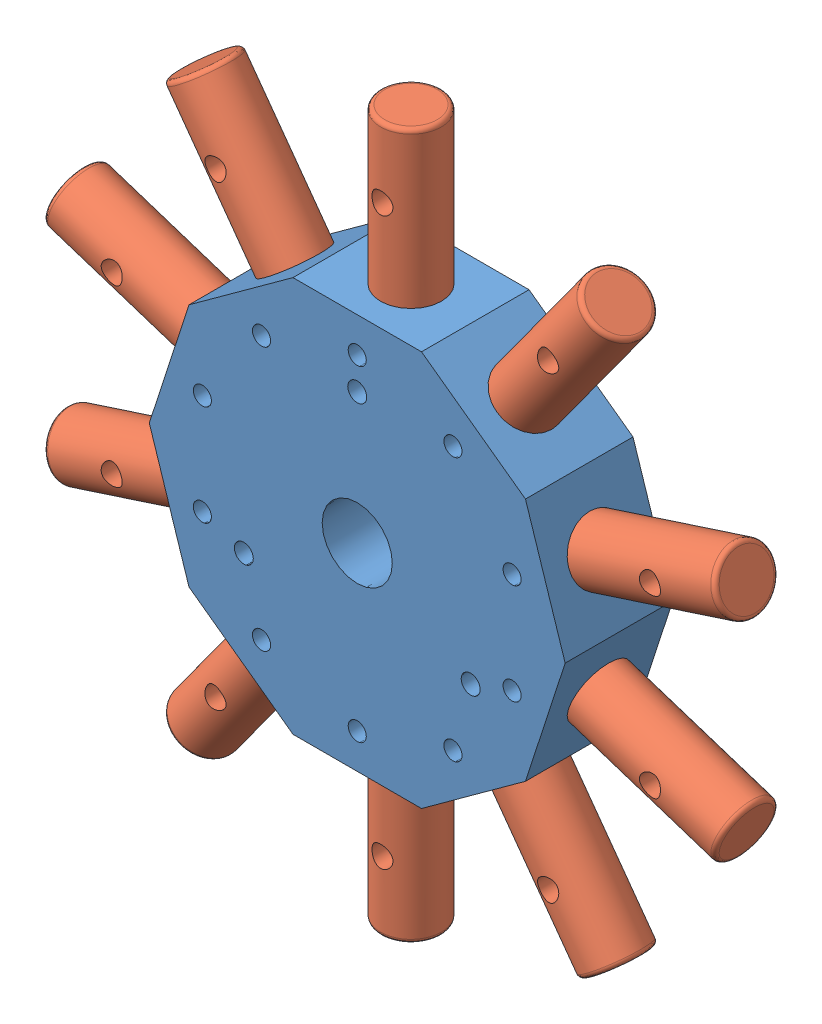
SolidWorks assembly RR2 Hub Subassembly, configuration Default. Lengths in mm.
Overall size (125.44 128.31 19.56).
11 component instances, 2 part files, 21 mates.
Components (placement in the parent):
- RR2 Hub Rev B-1: RR2 Hub Rev B [Default] at (9.4688 34.1785 19.558) size (75.62 71.92 19.56)
- RR2 Peg-1: RR2 Peg [Default] at (23.1405 52.9959 9.779) x (0.809017 -0.587785 0) z (0 0 1) size (11.05 40.89 11.05)
- RR2 Peg-2: RR2 Peg [Default] at (9.4688 57.4381 9.779) x (-1 0 0) z (0 0 -1) size (11.05 40.89 11.05)
- RR2 Peg-3: RR2 Peg [Default] at (31.5901 26.9908 9.779) x (-0.309017 -0.951057 0) z (0 0 1) size (11.05 40.89 11.05)
- RR2 Peg-4: RR2 Peg [Default] at (31.5901 41.3661 9.779) x (0.309017 -0.951057 0) z (0 0 1) size (11.05 40.89 11.05)
- RR2 Peg-5: RR2 Peg [Default] at (-4.2028 52.9959 9.779) x (0.809017 0.587785 0) z (0 0 1) size (11.05 40.89 11.05)
- RR2 Peg-6: RR2 Peg [Default] at (-12.6524 26.9908 9.779) x (-0.309017 0.951057 0) z (0 0 1) size (11.05 40.89 11.05)
- RR2 Peg-7: RR2 Peg [Default] at (-12.6524 41.3661 9.779) x (-0.309017 -0.951057 0) z (0 0 -1) size (11.05 40.89 11.05)
- RR2 Peg-8: RR2 Peg [Default] at (-4.2028 15.361 9.779) x (-0.809017 0.587785 0) z (0 0 1) size (11.05 40.89 11.05)
- RR2 Peg-9: RR2 Peg [Default] at (9.4688 10.9188 9.779) x (-1 0 0) z (0 0 1) size (11.05 40.89 11.05)
- RR2 Peg-10: RR2 Peg [Default] at (23.1405 15.361 9.779) x (0.809017 0.587785 0) z (0 0 -1) size (11.05 40.89 11.05)
Mates (geometry in assembly coordinates):
- Coincident1: coincident: plane of RR2 Hub Rev B-1 through (9.4688 34.1785 0) normal (0 0 -1); plane of assembly through (0 0 0) normal (0 0 1)
- Concentric1: concentric: cylinder of RR2 Hub Rev B-1 through (9.4688 57.4381 9.779) axis (0 1 0) radius 5.5499; cylinder of RR2 Peg-2 through (9.4688 98.3321 9.779) axis (0 -1 0) radius 5.5245
- Concentric2: concentric: cylinder of RR2 Hub Rev B-1 through (9.4688 63.7881 0) axis (0 0 1) radius 1.632; cylinder of RR2 Peg-2 through (9.4688 63.7881 15.3035) axis (0 0 -1) radius 1.632
- Concentric3: concentric: cylinder of RR2 Hub Rev B-1 through (23.1405 52.9959 9.779) axis (0.587785 0.809017 0) radius 5.5499; cylinder of RR2 Peg-1 through (47.1774 86.0799 9.779) axis (-0.587785 -0.809017 0) radius 5.5245
- Concentric4: concentric: cylinder of RR2 Hub Rev B-1 through (26.873 58.1332 0) axis (0 0 1) radius 1.632; cylinder of RR2 Peg-1 through (26.873 58.1332 4.2545) axis (0 0 1) radius 1.632
- Concentric5: concentric: cylinder of RR2 Hub Rev B-1 through (31.5901 41.3661 9.779) axis (0.951057 0.309017 0) radius 5.5499; cylinder of RR2 Peg-4 through (70.4826 54.003 9.779) axis (-0.951057 -0.309017 0) radius 5.5245
- Concentric6: concentric: cylinder of RR2 Hub Rev B-1 through (37.6293 43.3283 0) axis (0 0 1) radius 1.632; cylinder of RR2 Peg-4 through (37.6293 43.3283 4.2545) axis (0 0 1) radius 1.632
- Concentric7: concentric: cylinder of RR2 Hub Rev B-1 through (31.5901 26.9908 9.779) axis (0.951057 -0.309017 0) radius 5.5499; cylinder of RR2 Peg-3 through (70.4826 14.3539 9.779) axis (-0.951057 0.309017 0) radius 5.5245
- Concentric8: concentric: cylinder of RR2 Hub Rev B-1 through (37.6293 25.0286 0) axis (0 0 1) radius 1.632; cylinder of RR2 Peg-3 through (37.6293 25.0286 4.2545) axis (0 0 1) radius 1.632
- Concentric10: concentric: cylinder of RR2 Hub Rev B-1 through (-4.2028 52.9959 9.779) axis (-0.587785 0.809017 0) radius 5.5499; cylinder of RR2 Peg-5 through (-28.2397 86.0799 9.779) axis (0.587785 -0.809017 0) radius 5.5245
- Concentric11: concentric: cylinder of RR2 Hub Rev B-1 through (-7.9353 58.1332 0) axis (0 0 1) radius 1.632; cylinder of RR2 Peg-5 through (-7.9353 58.1332 4.2545) axis (0 0 1) radius 1.632
- Concentric12: concentric: cylinder of RR2 Hub Rev B-1 through (-12.6524 41.3661 9.779) axis (-0.951057 0.309017 0) radius 5.5499; cylinder of RR2 Peg-7 through (-51.5449 54.003 9.779) axis (0.951057 -0.309017 0) radius 5.5245
- Concentric13: concentric: cylinder of RR2 Hub Rev B-1 through (-18.6916 43.3283 0) axis (0 0 1) radius 1.632; cylinder of RR2 Peg-7 through (-18.6916 43.3283 15.3035) axis (0 0 -1) radius 1.632
- Concentric14: concentric: cylinder of RR2 Hub Rev B-1 through (-12.6524 26.9908 9.779) axis (-0.951057 -0.309017 0) radius 5.5499; cylinder of RR2 Peg-6 through (-51.5449 14.3539 9.779) axis (0.951057 0.309017 0) radius 5.5245
- Concentric15: concentric: cylinder of RR2 Hub Rev B-1 through (-18.6916 25.0286 0) axis (0 0 1) radius 1.632; cylinder of RR2 Peg-6 through (-18.6916 25.0286 4.2545) axis (0 0 1) radius 1.632
- Concentric17: concentric: cylinder of RR2 Hub Rev B-1 through (-4.2028 15.361 9.779) axis (-0.587785 -0.809017 0) radius 5.5499; cylinder of RR2 Peg-8 through (-28.2397 -17.7229 9.779) axis (0.587785 0.809017 0) radius 5.5245
- Concentric18: concentric: cylinder of RR2 Hub Rev B-1 through (-7.9353 10.2237 0) axis (0 0 1) radius 1.632; cylinder of RR2 Peg-8 through (-7.9353 10.2237 4.2545) axis (0 0 1) radius 1.632
- Concentric20: concentric: cylinder of RR2 Hub Rev B-1 through (9.4688 10.9188 9.779) axis (0 -1 0) radius 5.5499; cylinder of RR2 Peg-9 through (9.4688 -29.9752 9.779) axis (0 1 0) radius 5.5245
- Concentric21: concentric: cylinder of RR2 Hub Rev B-1 through (9.4688 4.5688 0) axis (0 0 1) radius 1.632; cylinder of RR2 Peg-9 through (9.4688 4.5688 4.2545) axis (0 0 1) radius 1.632
- Concentric22: concentric: cylinder of RR2 Hub Rev B-1 through (23.1405 15.361 9.779) axis (0.587785 -0.809017 0) radius 5.5499; cylinder of RR2 Peg-10 through (47.1774 -17.7229 9.779) axis (-0.587785 0.809017 0) radius 5.5245
- Concentric23: concentric: cylinder of RR2 Hub Rev B-1 through (26.873 10.2237 0) axis (0 0 1) radius 1.632; cylinder of RR2 Peg-10 through (26.873 10.2237 15.3035) axis (0 0 -1) radius 1.632
